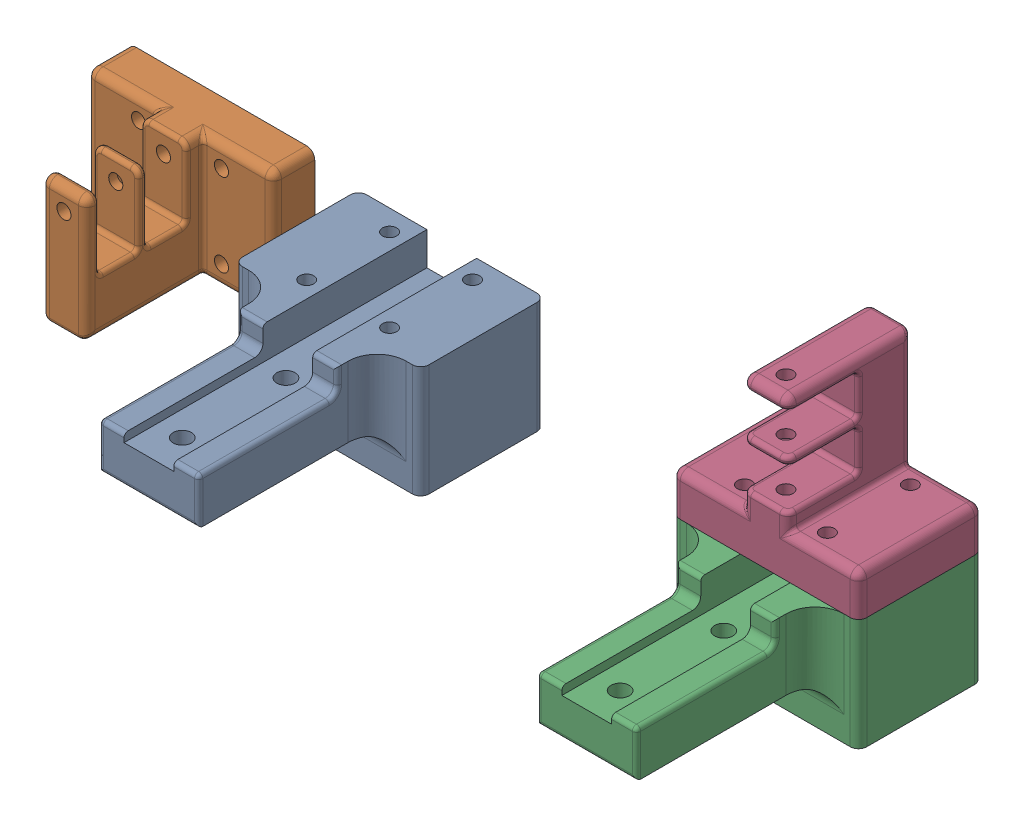
SolidWorks assembly comparison of pulley printingSLDASM, configuration Default. Lengths in mm.
Overall size (206.16 65 73.06).
4 component instances, 2 part files, 9 mates.
Components (placement in the parent):
- part1-final-1: part1-final [Default] at (-111.0813 27 15) size (45 27 73.06)
- Part2-1: Part2 [Default] at (-164.6274 15.1863 0) x (-1 0 0) z (0 -1 0) size (45 38 30)
- part1-final-2: part1-final [Default] at (-5.4709 27 15) size (45 27 73.06)
- Part2-2: Part2 [Default] at (-7.4752 27 15.1863) x (1 0 0) z (0 0 -1) size (45 38 30)
Mates (geometry in assembly coordinates):
- Coincident5: coincident anti-aligned: plane of part1-final-1 through (-111.0813 0 15) normal (0 -1 0)
- Coincident6: coincident anti-aligned: plane of Part2-1 through (-164.6274 0 10) normal (0 -1 0)
- Coincident8: coincident anti-aligned: plane of Part2-1 through (-164.6274 15.1863 0) normal (0 0 -1)
- Coincident10: coincident anti-aligned: plane of part1-final-2 through (-5.4709 27 15) normal (0 1 0); plane of Part2-2 through (-7.4752 27 15.1863) normal (0 -1 0)
- Coincident11: coincident aligned: plane of part1-final-2 through (-27.9709 10 15) normal (-1 0 0); plane of Part2-2 through (-27.9709 37 15.1863) normal (-1 0 0)
- Coincident12: coincident aligned: plane of part1-final-2 through (-5.4709 10 0) normal (0 0 -1); plane of Part2-2 through (-7.4752 37 0) normal (0 0 -1)
- Coincident13: coincident anti-aligned: plane of part1-final-2 through (-5.4709 10 0) normal (0 0 -1)
- Coincident14: coincident anti-aligned: plane of part1-final-2 through (-5.4709 0 15) normal (0 -1 0)
- Coincident17: coincident anti-aligned: plane of part1-final-1 through (-111.0813 10 0) normal (0 0 -1)
